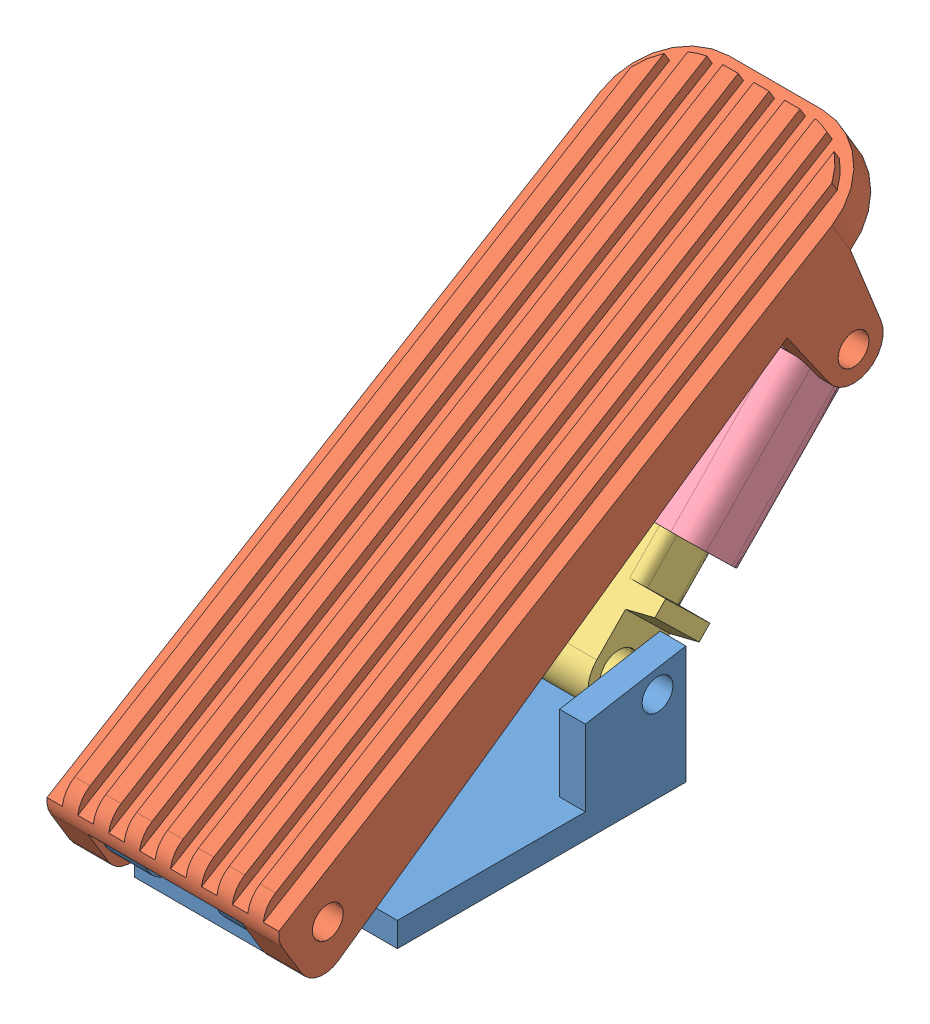
SolidWorks assembly Gas Pedal Assembly, configuration Default. Lengths in mm.
Overall size (57.15 124.11 171.52).
4 component instances, 4 part files, 9 mates.
Components (placement in the parent):
- Pedal Mount Bracket-1: Pedal Mount Bracket [Default] at (-11.1656 35.5497 109.0592) size (57.15 29.08 96.52)
- Pedal Face-1: Pedal Face [Default] at (-11.1656 36.3634 129.1844) x (1 0 0) z (0 0.855572 0.517684) size (57.15 177.8 37.48)
- Sensor Bottm-1: Sensor Bottm [Default] at (17.4094 60.6331 31.4877) x (0 0.715687 -0.698422) z (1 0 0) size (38.1 15.24 50.8)
- Sensor Top-1: Sensor Top [Default] at (43.1269 69.6049 20.0706) x (0 0.715687 -0.698422) z (1 0 0) size (50.8 19.05 53.98)
Mates (geometry in assembly coordinates):
- Concentric1: concentric aligned: cylinder of Pedal Mount Bracket-1 through (66.7536 49.8372 126.2042) axis (-1 0 0) radius 3.81; cylinder of Pedal Face-1 through (106.6904 49.8372 126.2042) axis (-1 0 0) radius 3.81
- Coincident3: coincident anti-aligned: plane of Pedal Mount Bracket-1 through (-1.6406 41.5822 109.0592) normal (-1 0 0); plane of Pedal Face-1 through (-1.6406 89.559 165.9698) normal (1 0 0)
- Concentric2: concentric anti-aligned: cylinder of Pedal Mount Bracket-1 through (79.8168 57.7747 44.9242) axis (-1 0 0) radius 3.81; cylinder of Sensor Bottm-1 through (-7.9906 57.7747 44.9242) axis (1 0 0) radius 4.7625
- Distance1: distance = 3.175 mm anti-aligned: plane of Pedal Mount Bracket-1 through (39.6344 35.5497 73.6897) normal (-1 0 0); plane of Sensor Bottm-1 through (36.4594 60.6331 31.4877) normal (1 0 0)
- Coincident5: coincident anti-aligned: plane of Sensor Bottm-1 through (17.4094 60.6331 31.4877) normal (0 -0.698422 -0.715687); plane of Sensor Top-1 through (36.4594 83.6603 9.016) normal (0 0.698422 0.715687)
- Coincident6: coincident anti-aligned: plane of Sensor Bottm-1 through (36.4594 60.6331 31.4877) normal (1 0 0); plane of Sensor Top-1 through (36.4594 83.6603 9.016) normal (-1 0 0)
- Concentric3: concentric anti-aligned: cylinder of Pedal Face-1 through (-4.8156 107.297 -3.4034) axis (-1 0 0) radius 3.81; cylinder of Sensor Top-1 through (-10.8481 107.297 -3.4034) axis (1 0 0) radius 3.81
- LimitDistance1: limit distance = 10.585 mm anti-aligned: plane of Sensor Top-1 through (43.1269 82.9098 33.7044) normal (0 -0.715687 0.698422); plane of Sensor Bottm-1 through (17.4094 63.3598 28.8267) normal (0 0.715687 -0.698422)
- LimitAngle2: limit planar angle = 0.611895 rad anti-aligned: plane of Pedal Mount Bracket-1 through (-11.1656 41.5822 109.0592) normal (0 1 0); plane of Pedal Face-1 through (138.6944 36.3634 129.1844) normal (0 -0.818561 -0.574419)
